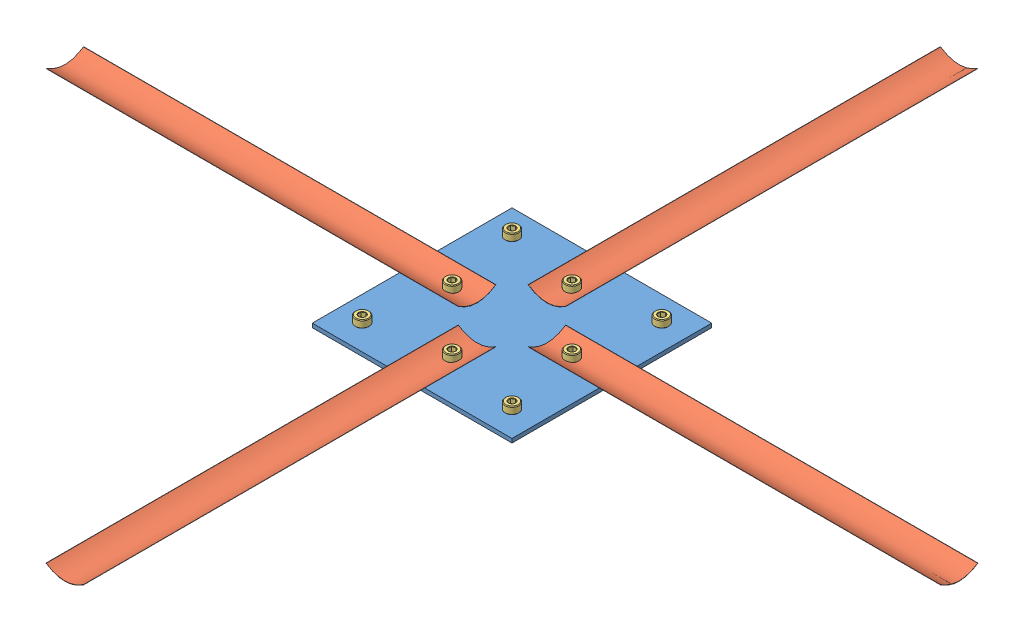
SolidWorks assembly AntennaAssembly, configuration Default. Lengths in mm.
Overall size (358.2 9.19 358.2).
17 component instances, 4 part files, 35 mates.
Components (placement in the parent):
- Z_Face_PCB-2: Z_Face_PCB [Default] at (-51.4977 -96.8 42.8879) size (80 1.6 80)
- 342MHZ_MONOPOLE_ANTENNA-1: 342MHZ_MONOPOLE_ANTENNA [Default] at (-3.4977 -95.2 -19.1121) x (1 0 0) z (0 1 0) size (15.1 165.1 2.64)
- 342MHZ_MONOPOLE_ANTENNA-2: 342MHZ_MONOPOLE_ANTENNA [Default] at (-17.4977 -95.2 -5.1121) x (0 0 -1) z (0 1 0) size (15.1 165.1 2.64)
- 342MHZ_MONOPOLE_ANTENNA-3: 342MHZ_MONOPOLE_ANTENNA [Default] at (-3.4977 -95.2 8.8879) x (-1 0 0) z (0 1 0) size (15.1 165.1 2.64)
- 342MHZ_MONOPOLE_ANTENNA-4: 342MHZ_MONOPOLE_ANTENNA [Default] at (10.5023 -95.2 -5.1121) x (0 0 1) z (0 1 0) size (15.1 165.1 2.64)
- M3_6MM_91292A111_TYPE 18-8 SS SOCKET HEAD CAP SCREW-1: M3_6MM_91292A111_TYPE 18-8 SS SOCKET HEAD CAP SCREW [91292A111] at (-3.4977 -101.2 18.8879) x (0.635565 0 -0.772047) z (0 -1 0) size (5.5 5.5 9.19)
- M3_6MM_91292A111_TYPE 18-8 SS SOCKET HEAD CAP SCREW-2: M3_6MM_91292A111_TYPE 18-8 SS SOCKET HEAD CAP SCREW [91292A111] at (26.5023 -101.2 -35.1121) x (1 0 0) z (0 -1 0) size (5.5 5.5 9.19)
- M3_6MM_91292A111_TYPE 18-8 SS SOCKET HEAD CAP SCREW-3: M3_6MM_91292A111_TYPE 18-8 SS SOCKET HEAD CAP SCREW [91292A111] at (26.5023 -101.2 24.8879) x (1 0 0) z (0 -1 0) size (5.5 5.5 9.19)
- M3_6MM_91292A111_TYPE 18-8 SS SOCKET HEAD CAP SCREW-4: M3_6MM_91292A111_TYPE 18-8 SS SOCKET HEAD CAP SCREW [91292A111] at (-3.4977 -101.2 -29.1121) x (1 0 0) z (0 -1 0) size (5.5 5.5 9.19)
- M3_6MM_91292A111_TYPE 18-8 SS SOCKET HEAD CAP SCREW-5: M3_6MM_91292A111_TYPE 18-8 SS SOCKET HEAD CAP SCREW [91292A111] at (20.5023 -101.2 -5.1121) x (0.882822 0 0.469708) z (0 -1 0) size (5.5 5.5 9.19)
- M3_6MM_91292A111_TYPE 18-8 SS SOCKET HEAD CAP SCREW-6: M3_6MM_91292A111_TYPE 18-8 SS SOCKET HEAD CAP SCREW [91292A111] at (-27.4977 -101.2 -5.1121) x (0.9999 0 0.014167) z (0 -1 0) size (5.5 5.5 9.19)
- M3_6MM_91292A111_TYPE 18-8 SS SOCKET HEAD CAP SCREW-7: M3_6MM_91292A111_TYPE 18-8 SS SOCKET HEAD CAP SCREW [91292A111] at (-33.4977 -101.2 24.8879) x (1 0 0) z (0 -1 0) size (5.5 5.5 9.19)
- M3_6MM_91292A111_TYPE 18-8 SS SOCKET HEAD CAP SCREW-8: M3_6MM_91292A111_TYPE 18-8 SS SOCKET HEAD CAP SCREW [91292A111] at (-33.4977 -101.2 -35.1121) x (1 0 0) z (0 -1 0) size (5.5 5.5 9.19)
- M3_05_NUT_91828A211_TYPE 18-8 STAINLESS STEEL HEX NUT-2: M3_05_NUT_91828A211_TYPE 18-8 STAINLESS STEEL HEX NUT [91828A211] at (-3.4977 -98 -29.1121) x (1 0 0) z (0 -1 0) size (5.5 6.35 2.78)
- M3_05_NUT_91828A211_TYPE 18-8 STAINLESS STEEL HEX NUT-3: M3_05_NUT_91828A211_TYPE 18-8 STAINLESS STEEL HEX NUT [91828A211] at (-27.4977 -98 -5.1121) x (0.982082 0 -0.188455) z (0 -1 0) size (5.5 6.35 2.78)
- M3_05_NUT_91828A211_TYPE 18-8 STAINLESS STEEL HEX NUT-5: M3_05_NUT_91828A211_TYPE 18-8 STAINLESS STEEL HEX NUT [91828A211] at (20.5023 -98 -5.1121) x (0.918365 0 -0.395734) z (0 -1 0) size (5.5 6.35 2.78)
- M3_05_NUT_91828A211_TYPE 18-8 STAINLESS STEEL HEX NUT-7: M3_05_NUT_91828A211_TYPE 18-8 STAINLESS STEEL HEX NUT [91828A211] at (-3.4977 -98 18.8879) x (0.8 0 -0.6) z (0 -1 0) size (5.5 6.35 2.78)
Mates (geometry in assembly coordinates):
- Concentric1: concentric anti-aligned: cylinder of Z_Face_PCB-2 through (-27.4977 -96.8 -5.1121) axis (0 1 0) radius 1.55; cylinder of 342MHZ_MONOPOLE_ANTENNA-2 through (-27.4977 -92.65 -5.1121) axis (0 -1 0) radius 1.5
- Concentric2: concentric anti-aligned: cylinder of Z_Face_PCB-2 through (-3.4977 -96.8 -29.1121) axis (0 1 0) radius 1.505; cylinder of 342MHZ_MONOPOLE_ANTENNA-1 through (-3.4977 -92.65 -29.1121) axis (0 -1 0) radius 1.5
- Concentric3: concentric anti-aligned: cylinder of Z_Face_PCB-2 through (-3.4977 -96.8 18.8879) axis (0 1 0) radius 1.505; cylinder of 342MHZ_MONOPOLE_ANTENNA-3 through (-3.4977 -92.65 18.8879) axis (0 -1 0) radius 1.5
- Concentric4: concentric anti-aligned: cylinder of Z_Face_PCB-2 through (20.5023 -96.8 -5.1121) axis (0 1 0) radius 1.55; cylinder of 342MHZ_MONOPOLE_ANTENNA-4 through (20.5023 -92.65 -5.1121) axis (0 -1 0) radius 1.5
- Concentric17: concentric anti-aligned: cylinder of Z_Face_PCB-2 through (-33.4977 -96.8 24.8879) axis (0 1 0) radius 1.505; cylinder of M3_6MM_91292A111_TYPE 18-8 SS SOCKET HEAD CAP SCREW-7 through (-33.4977 -92.2 24.8879) axis (0 -1 0) radius 2.75
- Concentric18: concentric anti-aligned: cylinder of Z_Face_PCB-2 through (26.5023 -96.8 24.8879) axis (0 1 0) radius 1.505; cylinder of M3_6MM_91292A111_TYPE 18-8 SS SOCKET HEAD CAP SCREW-3 through (26.5023 -92.2 24.8879) axis (0 -1 0) radius 2.75
- Concentric19: concentric anti-aligned: cylinder of Z_Face_PCB-2 through (-33.4977 -96.8 -35.1121) axis (0 1 0) radius 1.505; cylinder of M3_6MM_91292A111_TYPE 18-8 SS SOCKET HEAD CAP SCREW-8 through (-33.4977 -92.2 -35.1121) axis (0 -1 0) radius 2.75
- Concentric20: concentric anti-aligned: cylinder of Z_Face_PCB-2 through (26.5023 -96.8 -35.1121) axis (0 1 0) radius 1.505; cylinder of M3_6MM_91292A111_TYPE 18-8 SS SOCKET HEAD CAP SCREW-2 through (26.5023 -92.2 -35.1121) axis (0 -1 0) radius 2.75
- Concentric21: concentric anti-aligned: cylinder of Z_Face_PCB-2 through (-27.4977 -96.8 -5.1121) axis (0 1 0) radius 1.55; cylinder of M3_6MM_91292A111_TYPE 18-8 SS SOCKET HEAD CAP SCREW-6 through (-27.4977 -92.2 -5.1121) axis (0 -1 0) radius 2.75
- Concentric22: concentric anti-aligned: cylinder of Z_Face_PCB-2 through (-3.4977 -96.8 18.8879) axis (0 1 0) radius 1.505; cylinder of M3_6MM_91292A111_TYPE 18-8 SS SOCKET HEAD CAP SCREW-1 through (-3.4977 -92.2 18.8879) axis (0 -1 0) radius 2.75
- Concentric23: concentric anti-aligned: cylinder of Z_Face_PCB-2 through (-3.4977 -96.8 -29.1121) axis (0 1 0) radius 1.505; cylinder of M3_6MM_91292A111_TYPE 18-8 SS SOCKET HEAD CAP SCREW-4 through (-3.4977 -92.2 -29.1121) axis (0 -1 0) radius 2.75
- Concentric24: concentric anti-aligned: cylinder of Z_Face_PCB-2 through (20.5023 -96.8 -5.1121) axis (0 1 0) radius 1.55; cylinder of M3_6MM_91292A111_TYPE 18-8 SS SOCKET HEAD CAP SCREW-5 through (20.5023 -92.2 -5.1121) axis (0 -1 0) radius 2.75
- Coincident11: coincident anti-aligned: plane of Z_Face_PCB-2 through (-51.4977 -95.2 42.8879) normal (0 1 0); plane of M3_6MM_91292A111_TYPE 18-8 SS SOCKET HEAD CAP SCREW-3 through (26.5023 -95.2 24.8879) normal (0 -1 0)
- Coincident12: coincident anti-aligned: plane of Z_Face_PCB-2 through (-51.4977 -95.2 42.8879) normal (0 1 0); plane of M3_6MM_91292A111_TYPE 18-8 SS SOCKET HEAD CAP SCREW-1 through (-3.4977 -95.2 18.8879) normal (0 -1 0)
- Coincident13: coincident anti-aligned: plane of Z_Face_PCB-2 through (-51.4977 -95.2 42.8879) normal (0 1 0); plane of M3_6MM_91292A111_TYPE 18-8 SS SOCKET HEAD CAP SCREW-7 through (-33.4977 -95.2 24.8879) normal (0 -1 0)
- Coincident14: coincident anti-aligned: plane of Z_Face_PCB-2 through (-51.4977 -95.2 42.8879) normal (0 1 0); plane of M3_6MM_91292A111_TYPE 18-8 SS SOCKET HEAD CAP SCREW-5 through (20.5023 -95.2 -5.1121) normal (0 -1 0)
- Coincident15: coincident anti-aligned: plane of Z_Face_PCB-2 through (-51.4977 -95.2 42.8879) normal (0 1 0); plane of M3_6MM_91292A111_TYPE 18-8 SS SOCKET HEAD CAP SCREW-2 through (26.5023 -95.2 -35.1121) normal (0 -1 0)
- Coincident17: coincident anti-aligned: plane of Z_Face_PCB-2 through (-51.4977 -95.2 42.8879) normal (0 1 0); plane of M3_6MM_91292A111_TYPE 18-8 SS SOCKET HEAD CAP SCREW-8 through (-33.4977 -95.2 -35.1121) normal (0 -1 0)
- Coincident18: coincident anti-aligned: plane of Z_Face_PCB-2 through (-51.4977 -95.2 42.8879) normal (0 1 0); plane of M3_6MM_91292A111_TYPE 18-8 SS SOCKET HEAD CAP SCREW-6 through (-27.4977 -95.2 -5.1121) normal (0 -1 0)
- Parallel1: parallel aligned: line of Z_Face_PCB-2 through (36.5023 -95.2 34.8879) axis (0 0 -1); line of 342MHZ_MONOPOLE_ANTENNA-3 through (4.0523 -92.65 173.9879) axis (0 0 -1)
- Parallel2: parallel aligned: line of Z_Face_PCB-2 through (-43.4977 -95.2 34.8879) axis (1 0 0); line of 342MHZ_MONOPOLE_ANTENNA-2 through (-182.5977 -92.65 2.3379) axis (1 0 0)
- Parallel3: parallel anti-aligned: line of Z_Face_PCB-2 through (36.5023 -95.2 34.8879) axis (0 0 -1); line of 342MHZ_MONOPOLE_ANTENNA-1 through (4.0523 -92.65 -184.2121) axis (0 0 1)
- Parallel4: parallel aligned: line of Z_Face_PCB-2 through (36.5023 -95.2 -45.1121) axis (-1 0 0); line of 342MHZ_MONOPOLE_ANTENNA-4 through (175.6023 -92.65 -12.6621) axis (-1 0 0)
- Tangent1: tangent: plane of Z_Face_PCB-2 through (-51.4977 -95.2 42.8879) normal (0 1 0); curve of 342MHZ_MONOPOLE_ANTENNA-4
- Tangent2: tangent: plane of Z_Face_PCB-2 through (-51.4977 -95.2 42.8879) normal (0 1 0); curve of 342MHZ_MONOPOLE_ANTENNA-3
- Tangent3: tangent: plane of Z_Face_PCB-2 through (-51.4977 -95.2 42.8879) normal (0 1 0); curve of 342MHZ_MONOPOLE_ANTENNA-2
- Tangent4: tangent: plane of Z_Face_PCB-2 through (-51.4977 -95.2 42.8879) normal (0 1 0); curve of 342MHZ_MONOPOLE_ANTENNA-1
- Concentric33: concentric aligned: circle of M3_6MM_91292A111_TYPE 18-8 SS SOCKET HEAD CAP SCREW-4; cone of M3_05_NUT_91828A211_TYPE 18-8 STAINLESS STEEL HEX NUT-2 through (-3.4977 -96.8 -29.1121) axis (0 -1 0)
- Coincident29: coincident anti-aligned: plane of Z_Face_PCB-2 through (-51.4977 -96.8 42.8879) normal (0 -1 0); plane of M3_05_NUT_91828A211_TYPE 18-8 STAINLESS STEEL HEX NUT-2 through (-6.2477 -96.8 -27.5244) normal (0 1 0)
- Concentric34: concentric aligned: circle of M3_6MM_91292A111_TYPE 18-8 SS SOCKET HEAD CAP SCREW-6; cone of M3_05_NUT_91828A211_TYPE 18-8 STAINLESS STEEL HEX NUT-3 through (-27.4977 -96.8 -5.1121) axis (0 -1 0)
- Coincident30: coincident anti-aligned: plane of Z_Face_PCB-2 through (-51.4977 -96.8 42.8879) normal (0 -1 0); plane of M3_05_NUT_91828A211_TYPE 18-8 STAINLESS STEEL HEX NUT-3 through (-29.8993 -96.8 -3.0346) normal (0 1 0)
- Concentric35: concentric aligned: circle of M3_6MM_91292A111_TYPE 18-8 SS SOCKET HEAD CAP SCREW-5; cone of M3_05_NUT_91828A211_TYPE 18-8 STAINLESS STEEL HEX NUT-5 through (20.5023 -96.8 -5.1121) axis (0 -1 0)
- Coincident31: coincident anti-aligned: plane of Z_Face_PCB-2 through (-51.4977 -96.8 42.8879) normal (0 -1 0); plane of M3_05_NUT_91828A211_TYPE 18-8 STAINLESS STEEL HEX NUT-5 through (18.6051 -96.8 -2.5657) normal (0 1 0)
- Concentric36: concentric aligned: circle of M3_6MM_91292A111_TYPE 18-8 SS SOCKET HEAD CAP SCREW-1; cone of M3_05_NUT_91828A211_TYPE 18-8 STAINLESS STEEL HEX NUT-7 through (-3.4977 -96.8 18.8879) axis (0 -1 0)
- Coincident32: coincident anti-aligned: plane of Z_Face_PCB-2 through (-51.4977 -96.8 42.8879) normal (0 -1 0); plane of M3_05_NUT_91828A211_TYPE 18-8 STAINLESS STEEL HEX NUT-7 through (-4.7451 -96.8 21.8081) normal (0 1 0)
